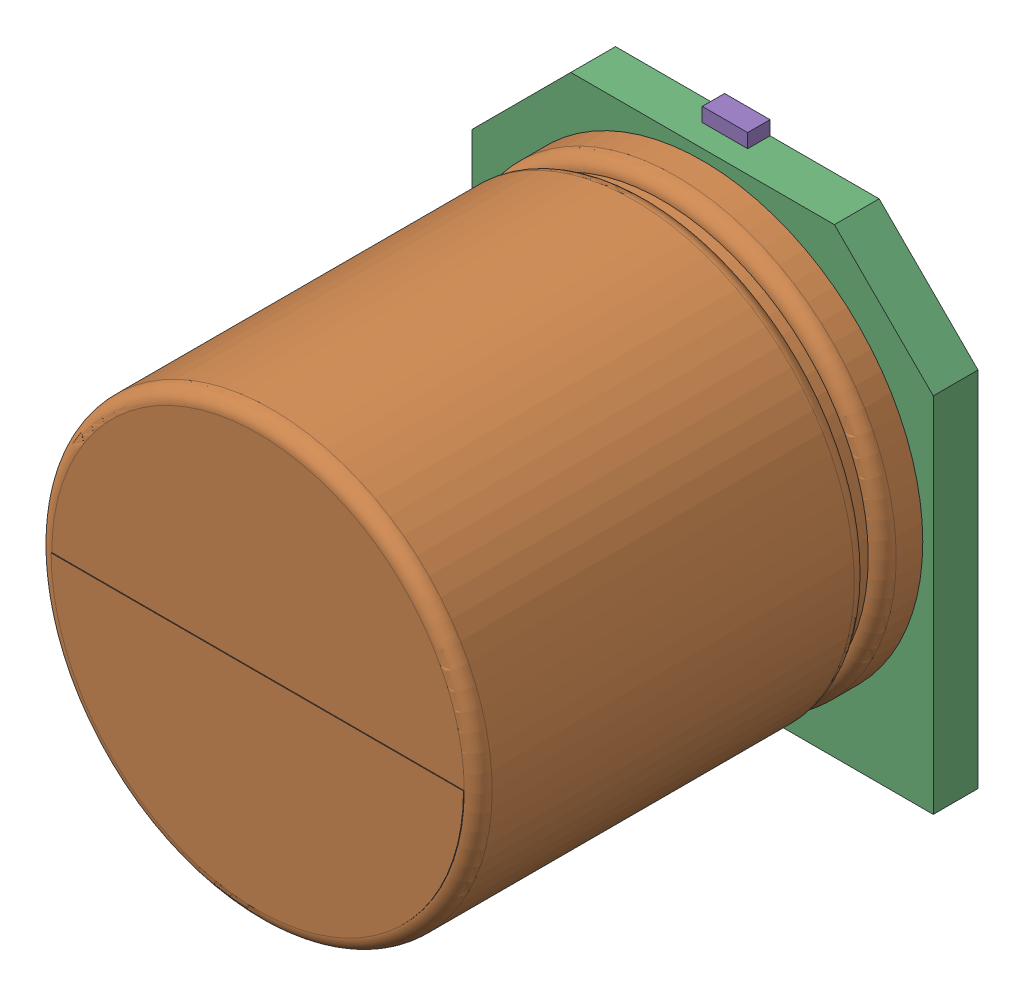
SolidWorks assembly C28, configuration Default. Lengths in mm.
Overall size (6.6 7 7.01).
6 component instances, 5 part files, 0 mates.
Components (placement in the parent):
- User_Library-CAPSMD6_3x7-1: User_Library-CAPSMD6_3x7 [Default] at (87.6314 26.9551 0) size (6.6 7 7.01)
  - User_Library-CAPSMD6_3x3_9_CAP003-1: User_Library-CAPSMD6_3x3_9_CAP003 [Default] at origin size (0.65 2.6 0.32)
  - User_Library-CAPSMD6_3x3_9_CAP-1: User_Library-CAPSMD6_3x3_9_CAP [Default] at origin size (6.3 6.3 6.37)
  - User_Library-CAPSMD6_3x3_9_CAP001-1: User_Library-CAPSMD6_3x3_9_CAP001 [Default] at origin size (6.6 6.6 0.64)
  - User_Library-CAPSMD6_3x3_9_CAP002-1: User_Library-CAPSMD6_3x3_9_CAP002 [Default] at origin size (5.11 1.47 0.01)
  - User_Library-CAPSMD6_3x3_9_CAP004-1: User_Library-CAPSMD6_3x3_9_CAP004 [Default] at origin size (0.65 2.6 0.32)
